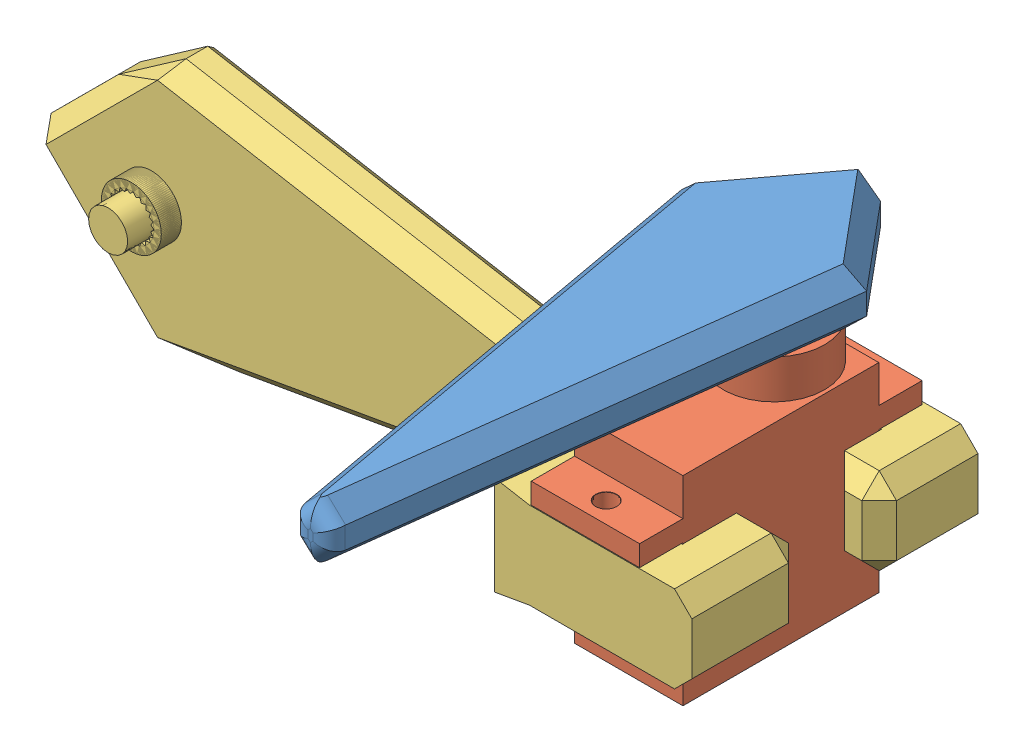
SolidWorks assembly left_legs_assembly, configuration Default. Lengths in mm.
Overall size (89.08 39.29 66.43).
3 component instances, 3 part files, 5 mates.
Components (placement in the parent):
- link_2_for_assembly-1: link_2_for_assembly [Default] at (61.965 85.974 165.4979) x (0.027082 0 0.999633) z (0 -1 0) size (65 20.81 9.5)
- sg90_model-1: sg90_model [Default] at (58.5484 53.974 174.5409) x (0 0 1) z (-1 0 0) size (32.6 27.5 12.5)
- left_link_1_for_assembly-1: left_link_1_for_assembly [Default] at (-8.0653 61.7735 176.2909) size (89.08 28.24 33.02)
Mates (geometry in assembly coordinates):
- Concentric4: concentric anti-aligned: circle of link_2_for_assembly-1; circle of sg90_model-1
- Coincident2: coincident anti-aligned: plane of link_2_for_assembly-1 through (58.5484 81.474 169.0909) normal (0 -1 0); plane of sg90_model-1 through (58.5484 81.474 169.0909) normal (0 1 0)
- Concentric5: concentric aligned: circle of sg90_model-1; circle of left_link_1_for_assembly-1
- Concentric6: concentric aligned: circle of sg90_model-1; circle of left_link_1_for_assembly-1
- Coincident3: coincident anti-aligned: plane of sg90_model-1 through (58.5484 70.274 174.5409) normal (0 -1 0); plane of left_link_1_for_assembly-1 through (-8.0653 70.274 176.2909) normal (0 1 0)
